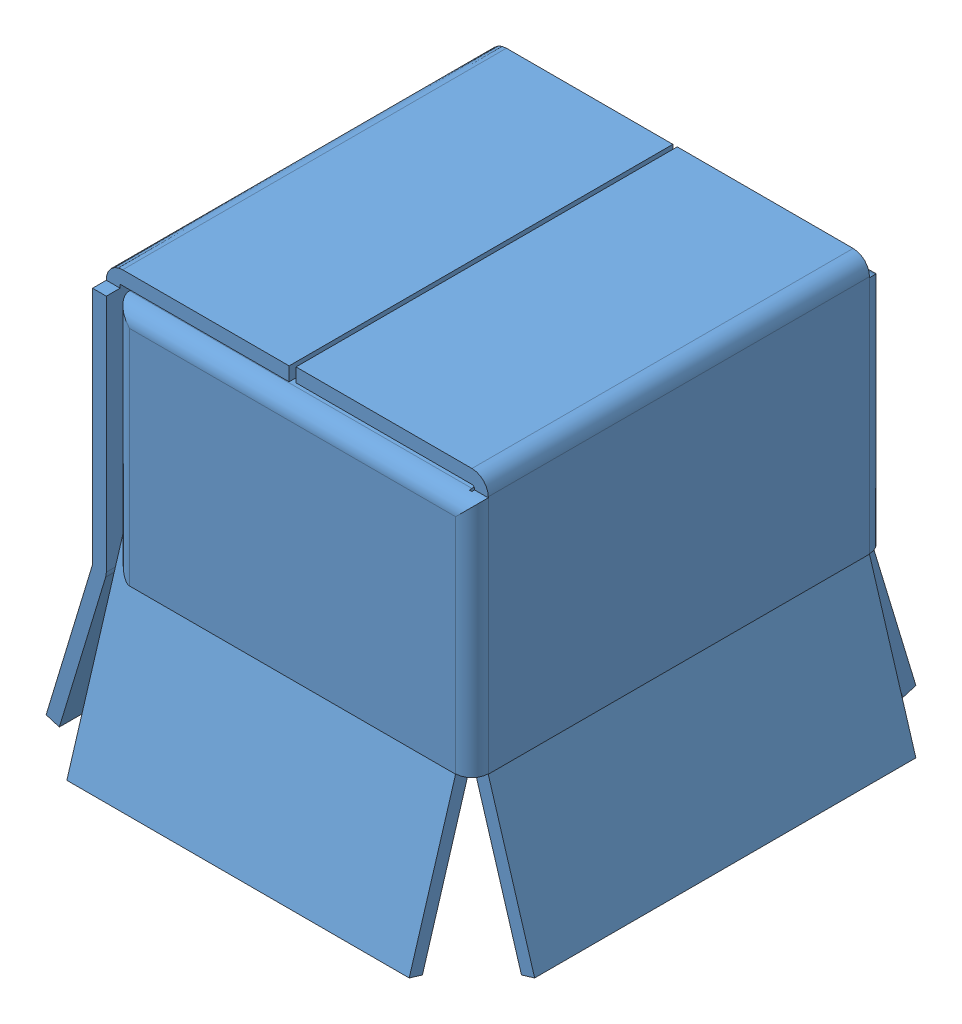
SolidWorks assembly Ensamblaje1, configuration Predeterminado. Lengths in mm.
Overall size (136.9 120 146.9).
4 component instances, 3 part files, 3 mates.
Components (placement in the parent):
- caja2017-1: caja2017 [Predeterminado] at (-13.8856 23.1974 -56) size (136.9 120 146.9)
- Ensamblaje del case-1: Ensamblaje del case [Predeterminado] at (-6.7356 51.0649 -9.6863) x (0 0 -1) z (-1 0 0) size (107 63.71 88.53)
  - Base2017-1: Base2017 [Predeterminado] at (-7.1863 -3.1325 0) size (107 18.75 87.7)
  - Tapa2017-1: Tapa2017 [Predeterminado] at (-7.1863 10.7175 0.8286) size (107 49.86 87.7)
Mates (geometry in assembly coordinates):
- Coincidente1: coincident: plane of caja2017-1 through (37.1144 23.1974 -56) normal (-1 0 0); plane of Ensamblaje del case-1/Base2017-1 through (37.1144 60.8411 -2.9141) normal (1 0 0)
- Coincidente2: coincident: line of caja2017-1 through (-64.149 54.1974 -56) axis (1 0 0); line of Ensamblaje del case-1/Base2017-1 through (-24.1756 54.1974 -56) axis (-1 0 0)
- Coincidente7: coincident anti-aligned: plane of caja2017-1 through (-62.8856 54.1974 10) normal (0 -1 0); plane of Ensamblaje del case-1/Base2017-1 through (-6.7356 54.1974 -2.5) normal (0 1 0)
